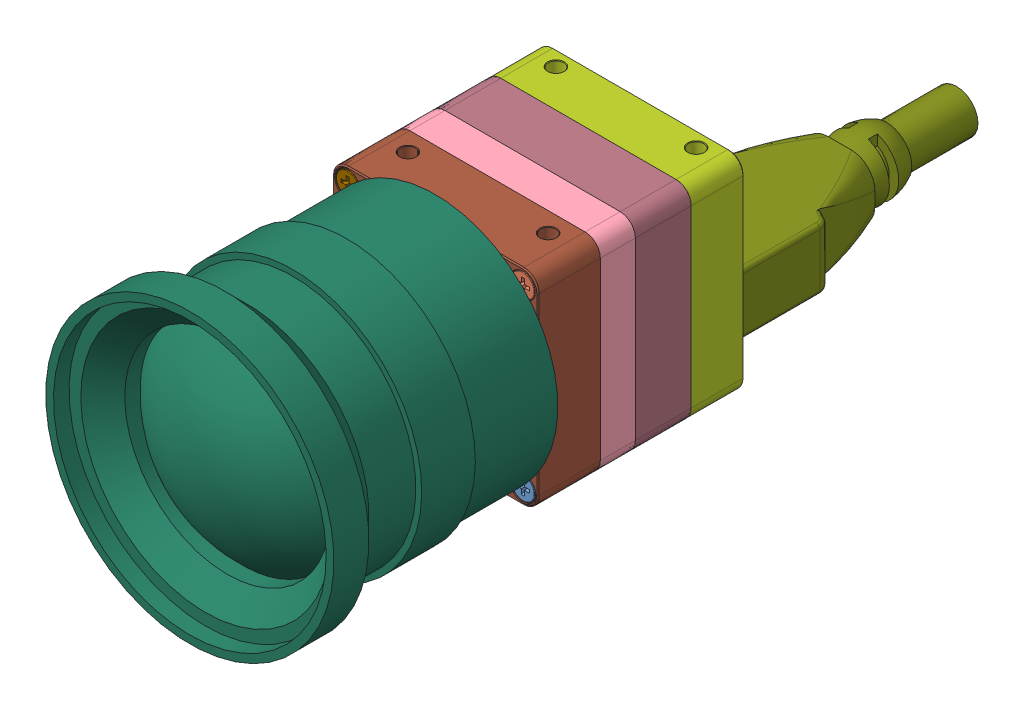
SolidWorks assembly xiq_asm, configuration Default. Lengths in mm.
Overall size (43.42 43.42 98.47).
35 component instances, 34 part files, 7 mates.
Components (placement in the parent):
- MQ013-E2-3: MQ013-E2 [Default] at (-45.0108 13.2 -18.97) x (1 0 0) z (0 0 -1) size (26.4 26.4 26.52)
  - 1-1: 1 [Default] at origin size (3 3 14.55)
  - 2-1: 2 [Default] at origin size (12.7 12.7 2.5)
  - 3-1: 3 [Default] at origin size (0.4 1.86 4.35)
  - 4-1: 4 [Default] at origin size (0.4 1.86 4.35)
  - 5-1: 5 [Default] at origin size (0.4 1.86 4.35)
  - 6-1: 6 [Default] at origin size (0.4 1.86 4.35)
  - 7-1: 7 [Default] at origin size (0.4 1.86 4.35)
  - 8-1: 8 [Default] at origin size (0.4 1.86 4.35)
  - 9-1: 9 [Default] at origin size (12.6 2.26 5)
  - 10-1: 10 [Default] at origin size (13.72 2.97 5.35)
  - 11-1: 11 [Default] at origin size (0.4 1.86 4.35)
  - 12-1: 12 [Default] at origin size (0.4 1.86 4.35)
  - 13-1: 13 [Default] at origin size (0.4 1.86 4.35)
  - 14-1: 14 [Default] at origin size (0.4 1.86 4.35)
  - 15-1: 15 [Default] at origin size (5 5 6)
  - 16-1: 16 [Default] at origin size (4 4 6.3)
  - 17-1: 17 [Default] at origin size (0.37 0.37 0.6)
  - 18-1: 18 [Default] at origin size (1.6 1.6 5.8)
  - 19-1: 19 [Default] at origin size (3 3 10.55)
  - 20-1: 20 [Default] at origin size (3 3 14.55)
  - 21-1: 21 [Default] at origin size (25.1 25.1 1.1)
  - 22-1: 22 [Default] at origin size (26.4 26.4 5)
  - 23-1: 23 [Default] at origin size (1.6 1.6 5.8)
  - 24-1: 24 [Default] at origin size (3 3 10.55)
  - 25-1: 25 [Default] at origin size (26.4 26.4 6.8)
  - 26-1: 26 [Default] at origin size (1.6 1.6 5.8)
  - 27-1: 27 [Default] at origin size (3 3 14.55)
  - 28-1: 28 [Default] at origin size (3 3 10.55)
  - 29-1: 29 [Default] at origin size (26.4 26.4 8)
  - 30-1: 30 [Default] at origin size (3 3 14.55)
  - 31-1: 31 [Default] at origin size (26.4 26.4 7.67)
  - 32-1: 32 [Default] at origin size (3 3 10.55)
- tamron_22HA-1: tamron_22HA [Default] at (-45.0108 13.2 -5) x (-0.192132 0.981369 0) z (0 0 1) size (37 37 36.5)
- micro_usb3_05-1: micro_usb3_05 [Default] at (-51.1461 3.7948 -26.47) size (15.6 9.42 46.1)
Mates (geometry in assembly coordinates):
- Concentric1: concentric aligned: cylinder of MQ013-E2-3/29-1 through (-45.0108 13.2 -79.2) axis (0 0 1) radius 12.2703; cylinder of tamron_22HA-1 through (-45.0108 13.2 30.4614) axis (0 0 1) radius 12.575
- Coincident1: coincident anti-aligned: plane of MQ013-E2-3/29-1 through (-31.8108 26.4 0) normal (0 0 1); plane of tamron_22HA-1 through (-57.3515 10.7839 0) normal (0 0 -1)
- Coincident2: coincident anti-aligned: plane of MQ013-E2-3/25-1 through (-58.2108 26.4 -26.47) normal (0 0 -1); plane of micro_usb3_05-1 through (-51.1461 3.7948 -26.47) normal (0 0 1)
- Width2: width anti-aligned: plane of micro_usb3_05-1 through (-46.9961 3.7948 -20.87) normal (0 -1 0); plane of micro_usb3_05-1 through (-51.1461 5.6248 -20.87) normal (0 1 0); plane of MQ013-E2-3/25-1 through (-50.9186 3.5198 -9.64) normal (0 1 0); plane of MQ013-E2-3/25-1 through (-39.1711 5.8998 -9.64) normal (0 -1 0)
- Width3: width aligned: plane of micro_usb3_05-1 through (-38.9461 5.6248 -20.87) normal (1 0 0); plane of micro_usb3_05-1 through (-51.1461 3.7948 -20.87) normal (-1 0 0); plane of MQ013-E2-3/25-1 through (-51.4211 4.7998 -9.64) normal (1 0 0); plane of MQ013-E2-3/25-1 through (-38.6711 4.6992 -9.64) normal (-1 0 0)
- Coincident4: coincident anti-aligned: plane of MQ013-E2-3/31-1 through (-31.8108 0 -19.67) normal (0 -1 0); plane of assembly through (0 0 0) normal (0 1 0)
- Coincident5: coincident aligned: plane of MQ013-E2-3/29-1 through (-31.8108 26.4 0) normal (0 0 1); plane of assembly through (0 0 0) normal (0 0 1)
